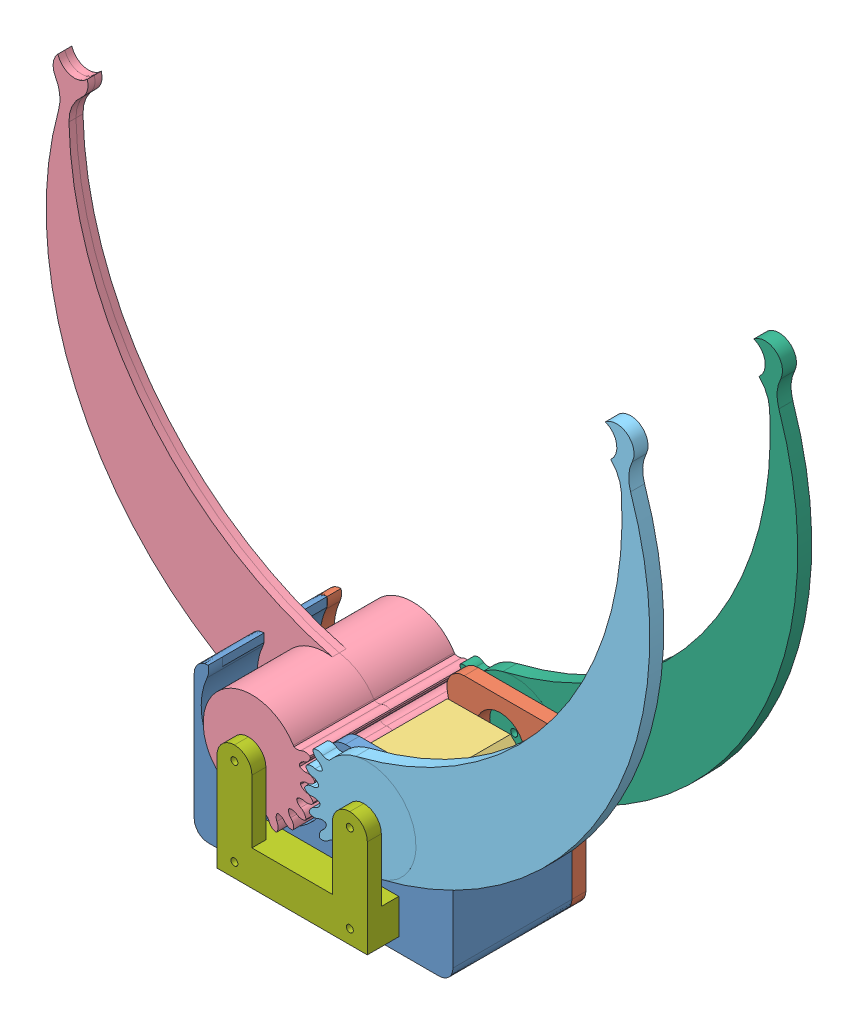
SolidWorks assembly Assemblage, configuration Défaut. Lengths in mm.
Overall size (242.28 168.3 56).
8 component instances, 7 part files, 19 mates.
Components (placement in the parent):
- Base-1: Base [Défaut] at (15.4736 -21.9653 82) size (74 44 34)
- Base - Copie-1: Base - Copie [Défaut] at (15.4736 -21.9653 48) size (74 44 4)
- XL-320-1: XL-320 [Défaut] at (11.2064 1.8213 58) x (0.999957 0.009265 0) z (0 0 1) size (24 36 27)
- Pièce1 - Copie (2)-1: Pièce1 - Copie (2) [Défaut] at (-21.7525 7.1227 44) x (-0.154003 0.98807 0) z (0 0 -1) size (151.65 85.15 46)
- Pièce1-1: Pièce1 [Défaut] at (11.2475 7.1227 86) x (-0.711813 0.702369 0) z (0 0 1) size (71.21 164.28 4)
- Pièce1 - Copie-1: Pièce1 - Copie [Défaut] at (11.2475 7.1227 44) x (-0.709396 0.70481 0) z (0 0 1) size (71.21 164.28 4)
- Bloqueur-1: Bloqueur [Défaut] at (-10.0025 -22.8617 95) x (-1 0 0) z (0 0 -1) size (43 33 9)
- Bloqueur-2: Bloqueur [Défaut] at (-0.5025 -22.8617 39) size (43 33 9)
Mates (geometry in assembly coordinates):
- Coaxiale1: concentric aligned: cylinder of Base-1 through (-21.7525 7.1227 82) axis (0 0 1) radius 18.5; cylinder of Base - Copie-1 through (-21.7525 7.1227 48) axis (0 0 1) radius 18.5
- Coaxiale2: concentric aligned: cylinder of Base-1 through (11.2475 7.1227 82) axis (0 0 1) radius 7; cylinder of Base - Copie-1 through (11.2475 7.1227 48) axis (0 0 1) radius 7
- Coïncidente1: coincident anti-aligned: plane of Base-1 through (15.4736 -21.9653 52) normal (0 0 -1); plane of Base - Copie-1 through (15.4736 -21.9653 52) normal (0 0 1)
- Coaxiale3: concentric anti-aligned: cylinder of Base-1 through (11.2475 7.1227 82) axis (0 0 1) radius 7; cylinder of XL-320-1 through (11.2475 7.1227 85) axis (0 0 -1) radius 6
- Coïncidente2: coincident anti-aligned: plane of Base-1 through (15.4736 -21.9653 82) normal (0 0 -1); plane of XL-320-1 through (11.2064 1.8213 82) normal (0 0 1)
- Coaxiale4: concentric aligned: circle of Base-1; circle of Pièce1 - Copie (2)-1
- Coaxiale5: concentric aligned: circle of Base-1; circle of Pièce1-1
- Coïncidente4: coincident anti-aligned: plane of Base-1 through (15.4736 -21.9653 86) normal (0 0 1); plane of Pièce1-1 through (11.2475 7.1227 86) normal (0 0 -1)
- Coaxiale6: concentric aligned: circle of Base - Copie-1; circle of Pièce1 - Copie-1
- Coïncidente5: coincident anti-aligned: plane of Base - Copie-1 through (15.4736 -21.9653 48) normal (0 0 -1); plane of Pièce1 - Copie-1 through (11.2475 7.1227 48) normal (0 0 1)
- Coaxiale7: concentric anti-aligned: circle of Base-1; circle of Bloqueur-1
- Coaxiale9: concentric anti-aligned: circle of Base-1; circle of Bloqueur-1
- Coaxiale10: concentric aligned: cylinder of Base - Copie-1 through (11.2475 -17.8773 48) axis (0 0 1) radius 1; cylinder of Bloqueur-2 through (11.2475 -17.8773 39) axis (0 0 1) radius 1
- Coaxiale11: concentric aligned: cylinder of Base - Copie-1 through (-21.7525 -17.8773 48) axis (0 0 1) radius 1; circle of Bloqueur-2
- Coïncidente6: coincident anti-aligned: plane of Base-1 through (15.4736 -21.9653 86) normal (0 0 1); plane of Bloqueur-1 through (-10.0025 -22.8617 86) normal (0 0 -1)
- Coïncidente7: coincident anti-aligned: plane of Base - Copie-1 through (15.4736 -21.9653 48) normal (0 0 -1); plane of Bloqueur-2 through (-0.5025 -22.8617 48) normal (0 0 1)
- Coïncidente9: coincident aligned: plane of Pièce1 - Copie (2)-1 through (-21.7525 7.1227 90) normal (0 0 1); plane of Pièce1-1 through (11.2475 7.1227 90) normal (0 0 1)
- Contr.Engrenages1: gear = 2 : 2 mm: cylinder of Pièce1 - Copie (2)-1 through (-21.7525 7.1227 90) axis (0 0 -1) radius 1; cylinder of Pièce1-1 through (11.2475 7.1227 86) axis (0 0 1) radius 1
- Contr.Engrenages2: gear = 2 : 2 mm: cylinder of Bloqueur-2 through (11.2475 7.1227 39) axis (0 0 1) radius 1; cylinder of Pièce1 - Copie (2)-1 through (-21.7525 7.1227 44) axis (0 0 1) radius 1
